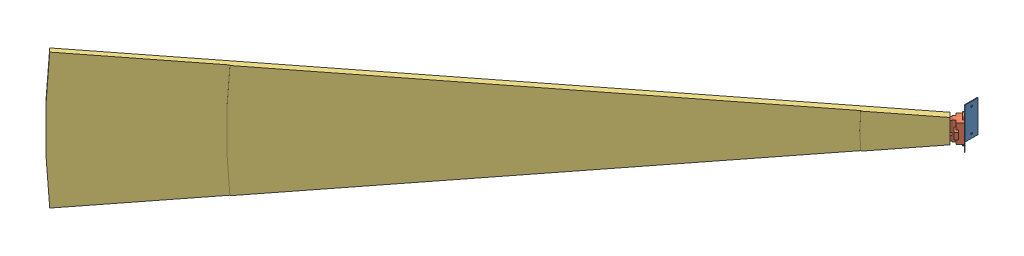
SolidWorks assembly capteur_cote, configuration Default. Lengths in mm.
Overall size (732.46 211.17 748.89).
3 component instances, 3 part files, 6 mates.
Components (placement in the parent):
- corniere_angle45_H50_l20-1: corniere_angle45_H50_l20 [Default] at (-21.0346 -24.5362 2.9851) size (15.14 50 34.85)
- GP2D12-1: GP2D12 [Default] at (-6.9885 -14.2862 17.0313) x (0 1 0) z (0.707107 0 0.707107) size (44.5 15.6 23.9)
- champ_GP2D12-1: champ_GP2D12 [Défaut] at (-28.8027 0.2138 17.2787) x (0 1 0) z (0.707107 0 -0.707107) size (211.17 10 1000)
Mates (geometry in assembly coordinates):
- Coïncidente1: coincident: plane of corniere_angle45_H50_l20-1 through (-6.5995 25.4638 17.4202) normal (-0.707107 0 0.707107); plane of GP2D12-1 through (-20.3528 -14.2862 3.6669) normal (0.707107 0 -0.707107)
- Coaxiale3: concentric: cylinder of corniere_angle45_H50_l20-1; cylinder of GP2D12-1
- Coaxiale4: concentric: cylinder of corniere_angle45_H50_l20-1; cylinder of GP2D12-1
- Coïncidente2: coincident: plane of ? through (-21.7316 18.8925 24.3498) normal (0.707107 0 -0.707107); plane of GP2D12-1 through (-27.2471 14.2638 18.8344) normal (-0.707107 0 0.707107)
- Coïncidente3: coincident: plane of ? through (127.7903 0.3925 -125.1721) normal (0.707107 0 0.707107); plane of GP2D12-1 through (-20.3174 -14.2862 22.9356) normal (0.707107 0 0.707107)
- Distance1: distance = 4 mm: line of champ_GP2D12-1; plane of GP2D12-1 through (-13.5645 -14.2862 23.6073) normal (0 -1 0)
